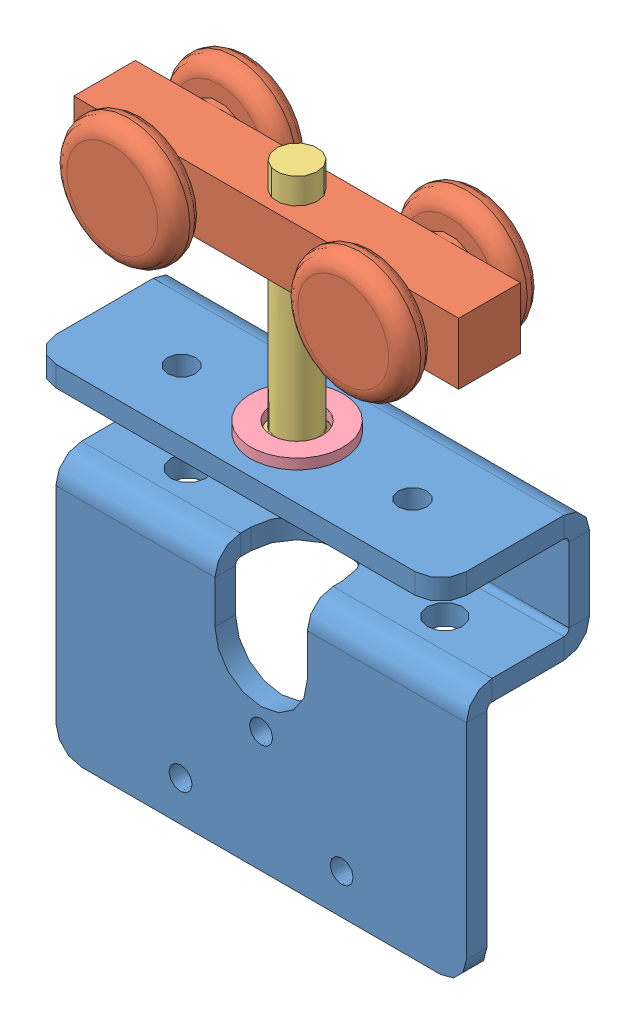
SolidWorks assembly B20-2K--3, configuration Default. Lengths in mm.
Overall size (80 117.5 30.5).
4 component instances, 4 part files, 0 mates.
Components (placement in the parent):
- G2311(Default)--1: G2311(Default)- [Default] at origin size (80 70.5 29)
- G2029--1: G2029- [Default] at (0 59.5 -3) x (0 0 -1) z (1 0 0) size (27 24 75)
- G2316(B18.3.5M - 8 x 1.25 x 50 Socket FCHS  -- 28S)--1: G2316(B18.3.5M - 8 x 1.25 x 50 Socket FCHS  -- 28S)- [Default] at (0 20.5 -3) x (0 1 0) z (-0.922323 0 0.386419) size (50 15.5 15.5)
- BRB-10x18x2--1: BRB-10x18x2- [Default] at (0 24.5 -3) size (18 2 18)
